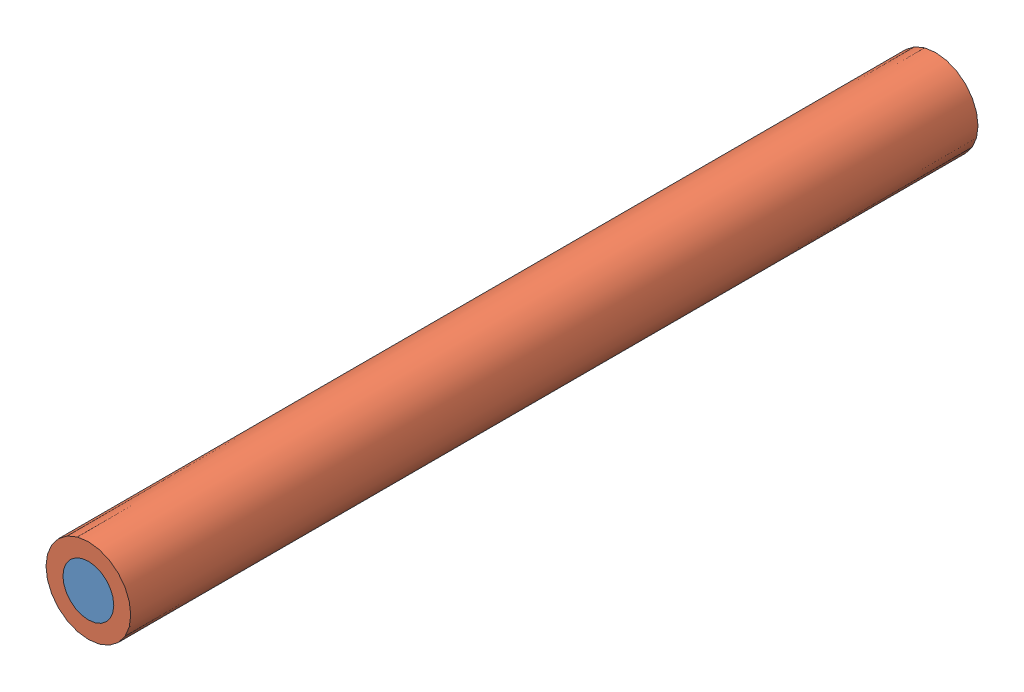
SolidWorks assembly Collared Shaft Assembly, configuration Default. Lengths in mm.
Overall size (500 500 5000).
2 component instances, 2 part files, 2 mates.
Components (placement in the parent):
- Shaft2-1: Shaft2 [Default] at (274.6265 500.5781 334.0951) size (300 300 5000)
- Shaft Collar-1: Shaft Collar [Default] at (274.6265 500.5781 334.0951) size (500 500 5000)
Mates (geometry in assembly coordinates):
- Concentric1: concentric aligned: cylinder of Shaft2-1 through (274.6265 500.5781 5334.0951) axis (0 0 -1) radius 150; cylinder of Shaft Collar-1 through (274.6265 500.5781 5334.0951) axis (0 0 -1) radius 250
- Coincident2: coincident aligned: plane of Shaft2-1 through (274.6265 500.5781 5334.0951) normal (0 0 1); plane of Shaft Collar-1 through (274.6265 500.5781 5334.0951) normal (0 0 1)
